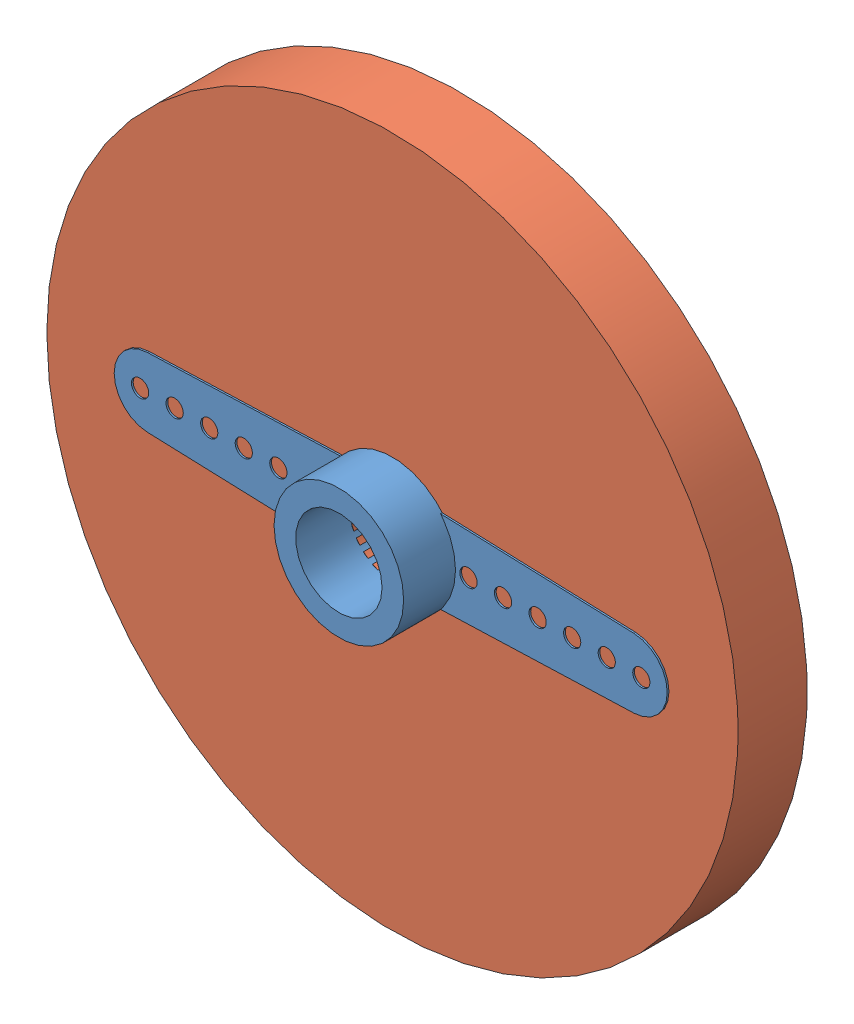
SolidWorks assembly Assem1, configuration Default. Lengths in mm.
Overall size (40 40 7.1).
2 component instances, 2 part files, 2 mates.
Components (placement in the parent):
- Microservo horn-1: Microservo horn [По умолчанию] at (26.1961 24.3359 18.2372) size (32 7.5 5)
- wheel40-1: wheel40 [Default] at (26.1961 24.3359 16.1372) size (40 40 4)
Mates (geometry in assembly coordinates):
- Concentric1: concentric: cylinder of Microservo horn-1 through (26.1961 24.3359 18.0372) axis (0 0 1) radius 2.5; cylinder of wheel40-1 through (26.1961 24.3359 16.1372) axis (0 0 1) radius 2.5
- Distance1: distance = 0.1 mm: plane of Microservo horn-1 through (26.1961 24.3359 20.2372) normal (0 0 1); plane of wheel40-1 through (26.1961 24.3359 20.1372) normal (0 0 1)
